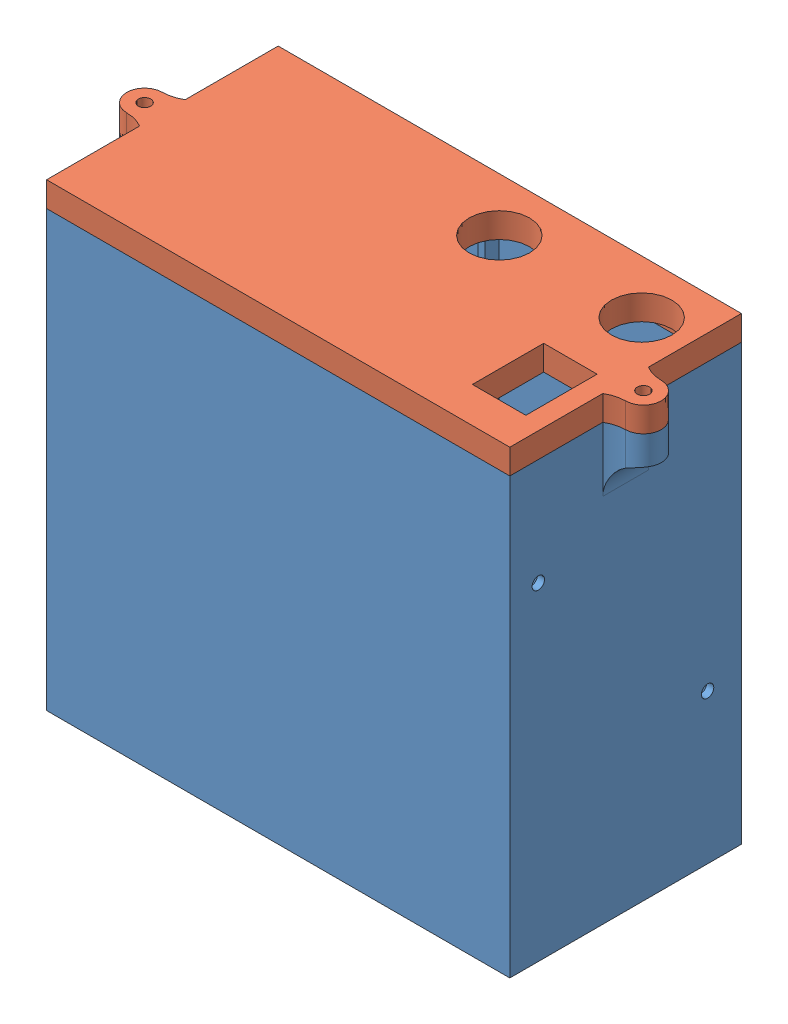
SolidWorks assembly Assem1, configuration Default. Lengths in mm.
Overall size (150 129 65).
2 component instances, 2 part files, 0 mates.
Components (placement in the parent):
- box-1: box [Default] at (63.1313 13.4675 113.9589) size (150 122 65)
- LID-1: LID [Default] at (0 135.4675 0) x (1 0 0) z (0 1 0) size (150 65 10)
